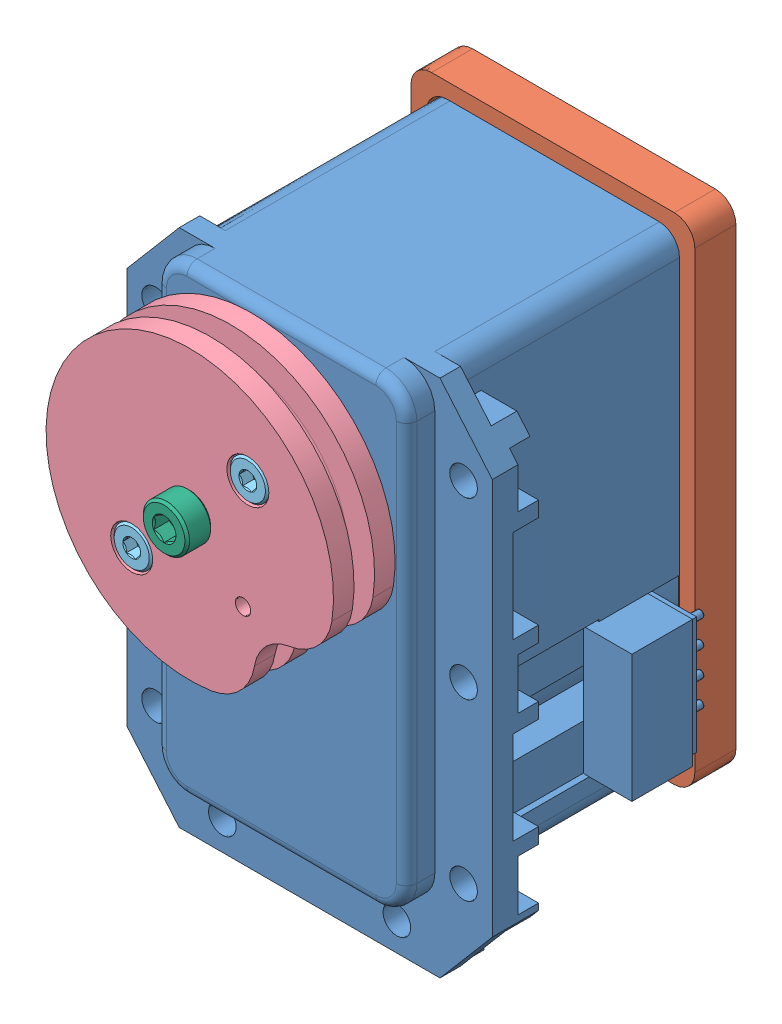
SolidWorks assembly block_actuator_pulley_o, configuration Default. Lengths in mm.
Overall size (38.36 58.4 45.54).
10 component instances, 6 part files, 20 mates.
Components (placement in the parent):
- dynamixel MX-28-exposed-1: dynamixel MX-28-exposed [Back Off] at origin size (35.6 50.6 39.77)
- d2_o-1: d2_o [Default] at (-12.375 -33.125 -8.75) x (0 1 0) z (0 0 -1) size (48.25 27.65 4)
- 91772A266 2-56 L5-4 pan-1: 91772A266 2-56 L5-4 pan [91772A266] at (-9.3 9 12.65) x (-0.205276 0.978704 0) z (0 0 -1) size (4.24 4.24 27.06)
- 91772A266 2-56 L5-4 pan-2: 91772A266 2-56 L5-4 pan [91772A266] at (9.2 9 12.65) x (-0.795891 0.60544 0) z (0 0 -1) size (4.24 4.24 27.06)
- 91772A266 2-56 L5-4 pan-3: 91772A266 2-56 L5-4 pan [91772A266] at (9.2 -30 12.65) x (-0.25415 0.967165 0) z (0 0 -1) size (4.24 4.24 27.06)
- 91772A266 2-56 L5-4 pan-4: 91772A266 2-56 L5-4 pan [91772A266] at (-9.3 -30 12.65) x (-0.098208 -0.995166 0) z (0 0 -1) size (4.24 4.24 27.06)
- b1_o-1: b1_o [Default] at (0 0 23.67) x (0.707107 -0.707107 0) z (0 0 1) size (26.25 28 6)
- 91290A012 M2 L5 socket-1: 91290A012 M2 L5 socket [91290A012] at (5.6569 5.6569 19.67) x (-0.923728 -0.383049 0) z (0 0 -1) size (3.8 3.8 7.09)
- 91290A012 M2 L5 socket-2: 91290A012 M2 L5 socket [91290A012] at (-5.6569 -5.6569 19.67) x (-0.923728 -0.383049 0) z (0 0 -1) size (3.8 3.8 7.09)
- 91292A012 M2.5 L8 socket-1: 91292A012 M2.5 L8 socket [91292A012] at (0 0 18.67) x (-0.476556 0.879144 0) z (0 0 -1) size (4.5 4.5 10.65)
Mates (geometry in assembly coordinates):
- Concentric2: concentric anti-aligned: cylinder of dynamixel MX-28-exposed-1 through (9.2 9 1.25) axis (0 0 -1) radius 1.15; cylinder of d2_o-1 through (9.2 9 -13.1906) axis (0 0 1) radius 1.075
- Parallel1: parallel aligned: plane of dynamixel MX-28-exposed-1 through (12.2 12 -17.75) normal (0 1 0); plane of d2_o-1 through (-13.875 13.625 -12.75) normal (0 1 0)
- Coincident2: coincident anti-aligned: plane of dynamixel MX-28-exposed-1 through (-10.2 -31 -8.75) normal (0 0 -1); plane of d2_o-1 through (-12.375 -33.125 -8.75) normal (0 0 1)
- Concentric4: concentric anti-aligned: cylinder of d2_o-1 through (-9.3 9 -13.1906) axis (0 0 1) radius 1.075; circle of 91772A266 2-56 L5-4 pan-1
- Coincident3: coincident anti-aligned: plane of d2_o-1 through (-12.375 -33.125 -12.75) normal (0 0 -1); plane of 91772A266 2-56 L5-4 pan-1 through (-9.3 9 -12.75) normal (0 0 1)
- Concentric5: concentric anti-aligned: cylinder of d2_o-1 through (9.2 9 -13.1906) axis (0 0 1) radius 1.075; circle of 91772A266 2-56 L5-4 pan-2
- Coincident4: coincident anti-aligned: plane of d2_o-1 through (-12.375 -33.125 -12.75) normal (0 0 -1); plane of 91772A266 2-56 L5-4 pan-2 through (9.2 9 -12.75) normal (0 0 1)
- Concentric6: concentric anti-aligned: cylinder of d2_o-1 through (9.2 -30 -13.1906) axis (0 0 1) radius 1.075; circle of 91772A266 2-56 L5-4 pan-3
- Coincident5: coincident aligned: plane of d2_o-1 through (-12.375 -33.125 -12.75) normal (0 0 -1); circle of 91772A266 2-56 L5-4 pan-3
- Concentric7: concentric anti-aligned: cylinder of d2_o-1 through (-9.3 -30 -13.1906) axis (0 0 1) radius 1.075; circle of 91772A266 2-56 L5-4 pan-4
- Coincident6: coincident anti-aligned: plane of d2_o-1 through (-12.375 -33.125 -12.75) normal (0 0 -1); plane of 91772A266 2-56 L5-4 pan-4 through (-9.3 -30 -12.75) normal (0 0 1)
- Concentric8: concentric aligned: cylinder of dynamixel MX-28-exposed-1 through (0 0 37.8337) axis (0 0 -1) radius 4; cylinder of b1_o-1 through (0 0 26.67) axis (0 0 -1) radius 4.175
- Coincident7: coincident anti-aligned: plane of dynamixel MX-28-exposed-1 through (0 0 23.52) normal (0 0 1); plane of b1_o-1 through (0 0 23.52) normal (0 0 -1)
- Concentric9: concentric aligned: circle of dynamixel MX-28-exposed-1; cylinder of b1_o-1 through (5.6569 5.6569 32.4683) axis (0 0 -1) radius 1.175
- Concentric10: concentric aligned: cylinder of b1_o-1 through (5.6569 5.6569 26.67) axis (0 0 -1) radius 2.05; cylinder of 91290A012 M2 L5 socket-1 through (5.6569 5.6569 26.67) axis (0 0 -1) radius 1.9
- Coincident8: coincident anti-aligned: plane of b1_o-1 through (0 0 24.67) normal (0 0 1); plane of 91290A012 M2 L5 socket-1 through (5.6569 5.6569 24.67) normal (0 0 -1)
- Concentric11: concentric aligned: cylinder of b1_o-1 through (-5.6569 -5.6569 26.67) axis (0 0 -1) radius 2.05; cylinder of 91290A012 M2 L5 socket-2 through (-5.6569 -5.6569 26.67) axis (0 0 -1) radius 1.9
- Coincident9: coincident anti-aligned: plane of b1_o-1 through (0 0 24.67) normal (0 0 1); plane of 91290A012 M2 L5 socket-2 through (-5.6569 -5.6569 24.67) normal (0 0 -1)
- Concentric12: concentric anti-aligned: cylinder of b1_o-1 through (0 0 8.8613) axis (0 0 1) radius 1.425; cylinder of 91292A012 M2.5 L8 socket-1 through (0 0 29.17) axis (0 0 -1) radius 2.25
- Coincident10: coincident anti-aligned: plane of b1_o-1 through (0 0 26.67) normal (0 0 1); plane of 91292A012 M2.5 L8 socket-1 through (0 0 26.67) normal (0 0 -1)
